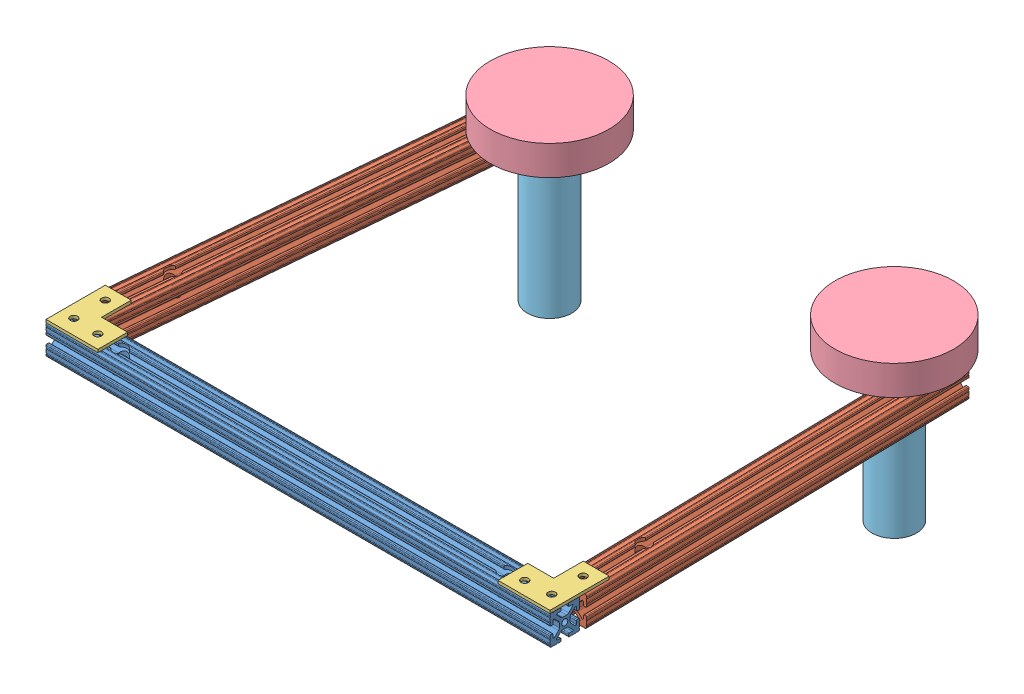
SolidWorks assembly Assem1, configuration Default. Lengths in mm.
Overall size (456.99 152.4 430.06).
9 component instances, 5 part files, 20 mates.
Components (placement in the parent):
- David 17 in T-Slot with holes-1: David 17 in T-Slot with holes [Default] at (-233.8334 148.4973 354.7376) size (431.8 25.73 25.4)
- modifiable_t-slot_bar__13.153_in_ with holes-1: modifiable_t-slot_bar__13.153_in_ with holes [Default] at (-315.6721 236.902 205.3633) x (-0.090615 0 0.995886) z (0 -1 0) size (334.09 25.4 25.73)
- modifiable_t-slot_bar__13.153_in_ with holes-2: modifiable_t-slot_bar__13.153_in_ with holes [Default] at (-8.0653 143.0119 201.721) x (0.019239 0 0.999815) z (0 1 0) size (334.09 25.4 25.73)
- David- link plate-1: David- link plate [Default] at (25.6828 205.197 388.9826) x (-1 0 0) z (0 0 1) size (44.45 2.54 50.8)
- David- link plate-2: David- link plate [Default] at (-361.6672 202.657 388.9826) size (44.45 2.54 50.8)
- 4in wheel-1: 4in wheel [Default] at (-0.8779 228.057 70.5497) x (0.644471 0 -0.764629) z (-0.764629 0 -0.644471) size (101.6 25.4 101.6)
- 4in wheel-2: 4in wheel [Default] at (-311.7444 202.657 55.042) x (0.820475 0 -0.571683) z (0.571683 0 0.820475) size (101.6 25.4 101.6)
- motor-1: motor [Default] at (-311.7444 75.657 55.042) x (1 0 -0.000011) z (0.000011 0 1) size (38.1 127 38.1)
- motor-2: motor [Default] at (-0.8779 75.657 70.5497) x (-1 0 0) z (0 0 -1) size (38.1 127 38.1)
Mates (geometry in assembly coordinates):
- Coincident1: coincident anti-aligned: plane of David 17 in T-Slot with holes-1 through (47.9078 202.657 414.3826) normal (0 1 0); plane of David- link plate-2 through (-361.6672 202.657 388.9826) normal (0 -1 0)
- Coincident2: coincident aligned: plane of David 17 in T-Slot with holes-1 through (-383.8922 177.257 414.3826) normal (-1 0 0); plane of David- link plate-2 through (-383.8922 205.197 414.3826) normal (-1 0 0)
- Coincident3: coincident aligned: plane of David 17 in T-Slot with holes-1 through (47.9078 177.257 414.3826) normal (0 0 1); plane of David- link plate-2 through (-339.4422 205.197 414.3826) normal (0 0 1)
- Coincident4: coincident anti-aligned: plane of David 17 in T-Slot with holes-1 through (47.9078 202.657 414.3826) normal (0 1 0); plane of David- link plate-1 through (25.6828 202.657 388.9826) normal (0 -1 0)
- Coincident5: coincident aligned: plane of David 17 in T-Slot with holes-1 through (47.9078 177.257 414.3826) normal (1 0 0); plane of David- link plate-1 through (47.9078 202.657 414.3826) normal (1 0 0)
- Coincident6: coincident aligned: plane of David 17 in T-Slot with holes-1 through (47.9078 177.257 414.3826) normal (0 0 1); plane of David- link plate-1 through (3.4578 202.657 414.3826) normal (0 0 1)
- Coincident7: coincident anti-aligned: plane of modifiable_t-slot_bar__13.153_in_ with holes-1 through (-360.9891 202.657 386.0276) normal (0 1 0); plane of David- link plate-2 through (-361.6672 202.657 388.9826) normal (0 -1 0)
- Concentric1: concentric anti-aligned: cylinder of modifiable_t-slot_bar__13.153_in_ with holes-1 through (-372.7162 211.6006 374.7586) axis (0 -1 0) radius 3.175; cylinder of David- link plate-2 through (-372.7162 202.657 374.7586) axis (0 1 0) radius 3.175
- Concentric2: concentric anti-aligned: cylinder of modifiable_t-slot_bar__13.153_in_ with holes-2 through (36.7318 168.3134 374.7586) axis (0 1 0) radius 3.175; cylinder of David- link plate-1 through (36.7318 205.197 374.7586) axis (0 -1 0) radius 3.175
- Coincident8: coincident anti-aligned: plane of modifiable_t-slot_bar__13.153_in_ with holes-2 through (24.2296 202.657 385.1611) normal (0 1 0); plane of David- link plate-1 through (25.6828 202.657 388.9826) normal (0 -1 0)
- Tangent3: tangent anti-aligned: plane of modifiable_t-slot_bar__13.153_in_ with holes-1 through (-360.9891 177.257 386.0276) normal (0.995886 0 0.090615); cylinder of motor-1 through (-311.7444 202.657 55.042) axis (0 -1 0) radius 19.05
- Coincident10: coincident aligned: plane of modifiable_t-slot_bar__13.153_in_ with holes-1 through (-360.9891 202.657 386.0276) normal (0 1 0); plane of motor-1 through (-311.7444 202.657 55.042) normal (0 1 0)
- Distance1: distance = 0 mm: plane of modifiable_t-slot_bar__13.153_in_ with holes-1 through (-330.716 177.257 53.3158) normal (0.090615 0 -0.995886); cylinder of motor-1 through (-311.7444 202.657 55.042) axis (0 -1 0) radius 19.05
- Coincident11: coincident anti-aligned: plane of 4in wheel-2 through (-311.7444 202.657 55.042) normal (0 -1 0); plane of motor-1 through (-311.7444 202.657 55.042) normal (0 1 0)
- Concentric3: concentric aligned: cylinder of 4in wheel-2 through (-311.7444 228.057 55.042) axis (0 -1 0) radius 50.8; cylinder of motor-1 through (-311.7444 202.657 55.042) axis (0 -1 0) radius 19.05
- Coincident12: coincident anti-aligned: plane of 4in wheel-1 through (-0.8779 202.657 70.5497) normal (0 -1 0); plane of motor-2 through (-0.8779 202.657 70.5497) normal (0 1 0)
- Concentric4: concentric anti-aligned: cylinder of 4in wheel-1 through (-0.8779 202.657 70.5497) axis (0 1 0) radius 50.8; cylinder of motor-2 through (-0.8779 202.657 70.5497) axis (0 -1 0) radius 19.05
- Tangent5: tangent anti-aligned: plane of modifiable_t-slot_bar__13.153_in_ with holes-2 through (24.2296 202.657 385.1611) normal (-0.999815 0 0.019239); cylinder of motor-2 through (-0.8779 202.657 70.5497) axis (0 -1 0) radius 19.05
- Coincident13: coincident anti-aligned: plane of modifiable_t-slot_bar__13.153_in_ with holes-2 through (24.2296 202.657 385.1611) normal (0 1 0); plane of 4in wheel-1 through (-0.8779 202.657 70.5497) normal (0 -1 0)
- Tangent6: tangent aligned: plane of modifiable_t-slot_bar__13.153_in_ with holes-2 through (17.802 202.657 51.1367) normal (-0.019239 0 -0.999815); cylinder of motor-2 through (-0.8779 202.657 70.5497) axis (0 -1 0) radius 19.05
